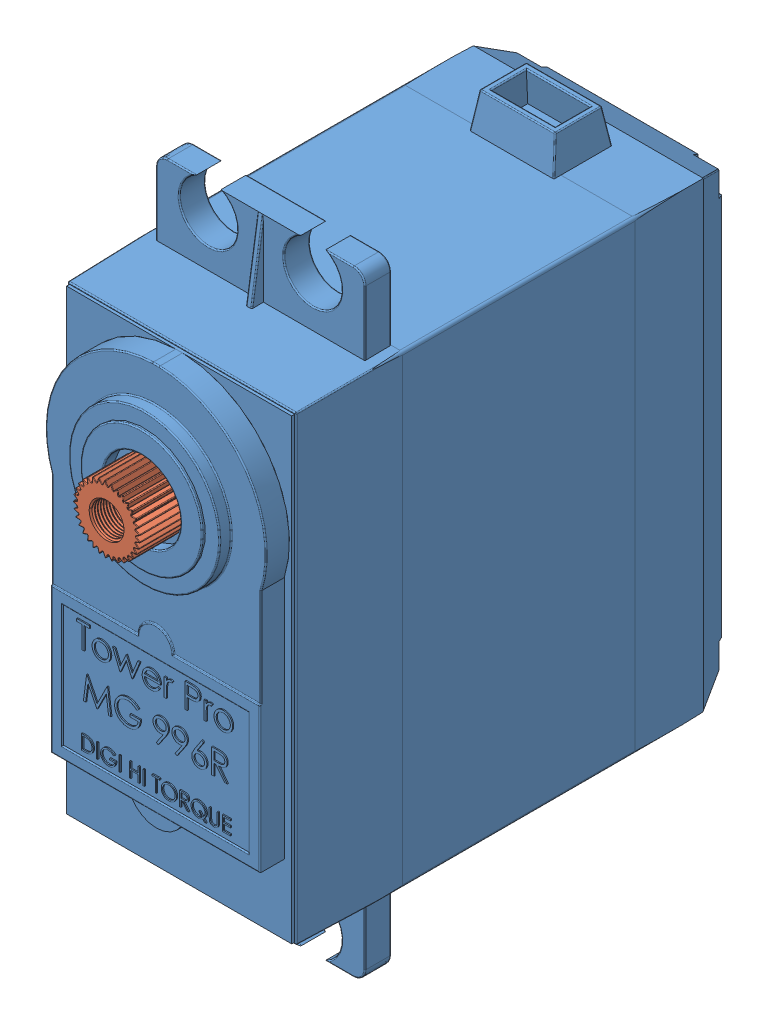
SolidWorks assembly main_assembly, configuration Default. Lengths in mm.
Overall size (20 53 44.5).
2 component instances, 2 part files, 2 mates.
Components (placement in the parent):
- main_body-1: main_body [Default] at (15.1003 34.2066 38.7045) size (20 53 41.5)
- gear-1: gear [Default] at (15.0988 44.3995 70.2045) x (0.991102 -0.133104 0) z (0 0 1) size (5.74 5.74 4.11)
Mates (geometry in assembly coordinates):
- Concentric1: concentric: circle of main_body-1; circle of gear-1
- Coincident2: coincident: plane of main_body-1 through (15.0988 44.3995 70.2045) normal (0 0 1); plane of gear-1 through (15.0988 44.3995 70.2045) normal (0 0 -1)
